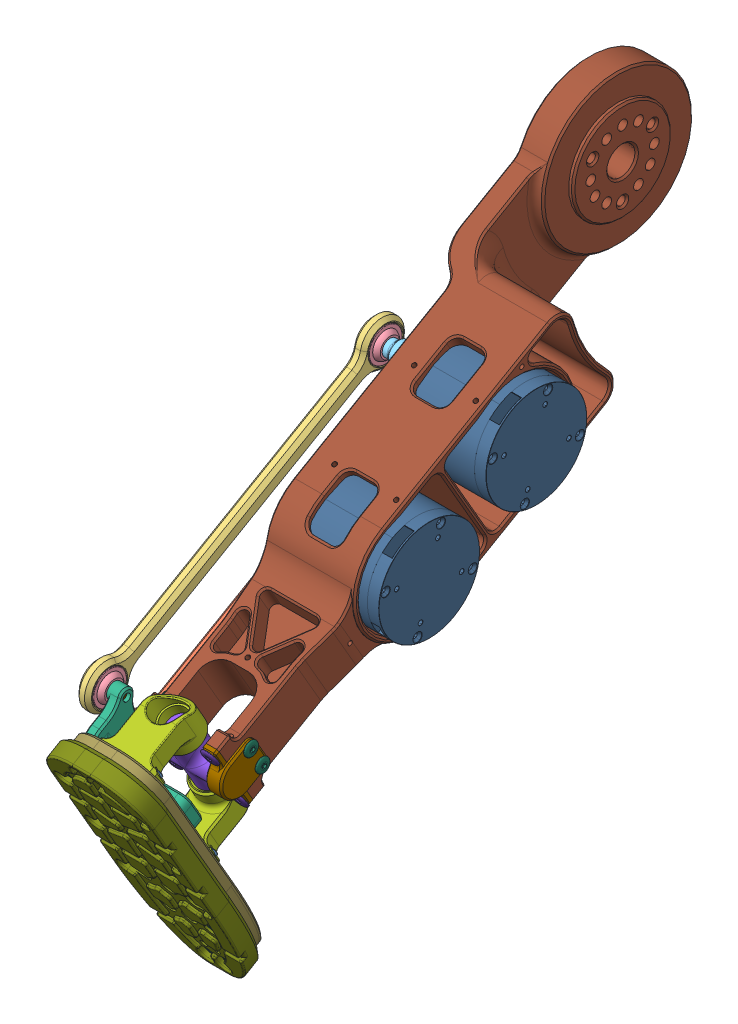
SolidWorks assembly 脚部装配体, configuration 默认. Lengths in mm.
Overall size (85.06 414.51 476.41).
79 component instances, 18 part files, 169 mates.
Components (placement in the parent):
- GB╱T 70.1-2008[内六角圆柱头螺钉M5×10].step-1: GB╱T 70.1-2008[内六角圆柱头螺钉M5×10].step [默认] at (53.6753 -418.9952 565.7229) x (0 0.5 -0.866025) z (0.926695 -0.325466 -0.187908) size (15 8.5 8.5)
- GB╱T 70.1-2008[内六角圆柱头螺钉M5×10].step-2: GB╱T 70.1-2008[内六角圆柱头螺钉M5×10].step [默认] at (67.1753 -418.9952 565.7229) x (0 0.5 -0.866025) z (0.969283 -0.212997 -0.122974) size (15 8.5 8.5)
- GB╱T 70.1-2008[内六角圆柱头螺钉M5×10].step-3: GB╱T 70.1-2008[内六角圆柱头螺钉M5×10].step [默认] at (40.1753 -365.3016 596.7229) x (0 0.5 -0.866025) z (0.993521 -0.098424 -0.056825) size (15 8.5 8.5)
- GB╱T 70.1-2008[内六角圆柱头螺钉M5×10].step-4: GB╱T 70.1-2008[内六角圆柱头螺钉M5×10].step [默认] at (53.6753 -365.3016 596.7229) x (0 0.5 -0.866025) z (1 0.000593 0.000342) size (15 8.5 8.5)
- GB╱T 70.1-2008[内六角圆柱头螺钉M5×10].step-5: GB╱T 70.1-2008[内六角圆柱头螺钉M5×10].step [默认] at (41.1753 -396.4785 578.7229) x (0 0.5 -0.866025) z (0.990502 0.119076 0.068749) size (15 8.5 8.5)
- GB╱T 70.1-2008[内六角圆柱头螺钉M5×10].step-6: GB╱T 70.1-2008[内六角圆柱头螺钉M5×10].step [默认] at (67.1753 -365.3016 596.7229) x (0 0.5 -0.866025) z (0.996407 0.073345 0.042346) size (15 8.5 8.5)
- GB╱T 70.1-2008[内六角圆柱头螺钉M5×10].step-7: GB╱T 70.1-2008[内六角圆柱头螺钉M5×10].step [默认] at (66.1753 -387.8182 583.7229) x (0 0.5 -0.866025) z (0.988477 0.13109 0.075685) size (15 8.5 8.5)
- GB╱T 70.1-2008[内六角圆柱头螺钉M5×10].step-8: GB╱T 70.1-2008[内六角圆柱头螺钉M5×10].step [默认] at (66.1753 -396.4785 578.7229) x (0 0.5 -0.866025) z (0.990906 0.116532 0.06728) size (15 8.5 8.5)
- 短连杆-1: 短连杆 [默认] at (5.8253 -352.7894 433.0512) x (0 0.5 -0.866025) z (-1 0 0) size (135 25 7)
- 长连杆-1: 长连杆 [默认] at (5.8253 -286.4689 358.1807) x (0 0.866025 0.5) z (-1 0 0) size (25 205 7)
- 镜向GB╱T 9163-2001[向心关节轴承（G系列）8]-1: 镜向GB╱T 9163-2001[向心关节轴承（G系列）8] [8] at (11.3253 -335.4689 443.0512) x (1 0 0) z (0 -0.949949 -0.312405) size (11 19 19)
- 镜向GB╱T 9163-2001[向心关节轴承（G系列）8]-2: 镜向GB╱T 9163-2001[向心关节轴承（G系列）8] [8] at (11.3253 -390.4689 538.314) x (1 0 0) z (0 -0.950599 -0.310421) size (11 19 19)
- 镜向GB╱T 9163-2001[向心关节轴承（G系列）8]-3: 镜向GB╱T 9163-2001[向心关节轴承（G系列）8] [8] at (11.3253 -265.8279 402.4294) x (1 0 0) z (0 -0.949949 -0.312405) size (11 19 19)
- 镜向GB╱T 9163-2001[向心关节轴承（G系列）8]-4: 镜向GB╱T 9163-2001[向心关节轴承（G系列）8] [8] at (11.3253 -355.8279 558.314) x (1 0 0) z (0 -0.950599 -0.310421) size (11 19 19)
- 输出法兰连杆-1: 输出法兰连杆 [默认] at (33.0753 -318.1484 453.0512) x (0 -0.5 0.866025) z (-1 0 0) size (35 46.68 33.25)
- 输出法兰连杆-2: 输出法兰连杆 [默认] at (33.0753 -283.1484 392.4294) x (0 0.5 -0.866025) z (-1 0 0) size (35 46.68 33.25)
- 脚底连杆-1: 脚底连杆 [默认] at (53.6753 -369.8279 582.5627) x (0 -0.866025 -0.5) z (0 0.5 -0.866025) size (49 65.35 38.5)
- 脚踝横滚连接件-1: 脚踝横滚连接件 [默认] at (53.6753 -355.8279 558.314) x (0 0.5 -0.866025) z (0 0.866025 0.5) size (40.5 33 22.07)
- 脚踝横滚连接件-2: 脚踝横滚连接件 [默认] at (53.6753 -390.4689 538.314) x (0 0.5 -0.866025) z (0 -0.866025 -0.5) size (40.5 33 22.07)
- 镜向16x40十字轴承-1: 镜向16x40十字轴承 [默认] at (53.6753 -373.1484 548.314) x (1 0 0) z (0 -0.5 0.866025) size (40 40 16)
- 小腿轴承锁-1: 小腿轴承锁 [默认] at (34.3253 -373.1484 548.314) x (0 -0.866025 -0.5) z (0 -0.5 0.866025) size (40 8.92 25.5)
- 小腿轴承锁-2: 小腿轴承锁 [默认] at (73.0253 -373.1484 548.314) x (0 0.866025 0.5) z (0 -0.5 0.866025) size (40 8.92 25.5)
- DM 4340 rau 3505 电机 3D-1: DM 4340 rau 3505 电机 3D [默认] at (33.0753 -318.1484 453.0512) x (0 -0.5 0.866025) z (0 0.866025 0.5) size (57 56.5 57)
- 小腿-1: 小腿 [默认] at (34.3253 -223.1484 288.5064) x (0 0.866025 0.5) z (-1 0 0) size (219.14 409.57 65)
- DM 4340 rau 3505 电机 3D-2: DM 4340 rau 3505 电机 3D [默认] at (33.0753 -283.1484 392.4294) x (0 0.5 -0.866025) z (0 -0.866025 -0.5) size (57 56.5 57)
- 脚底板-1: 脚底板 [默认] at (53.6753 -405.4689 564.2947) x (0 -0.866025 -0.5) z (0 -0.5 0.866025) size (150.3 50.4 10.3)
- GB╱T 70.1-2008[内六角圆柱头螺钉M5×10].step-9: GB╱T 70.1-2008[内六角圆柱头螺钉M5×10].step [默认] at (41.1753 -387.8182 583.7229) x (0 0.5 -0.866025) z (0.995522 0.081868 0.047267) size (15 8.5 8.5)
- GB╱T 70.1-2008[内六角圆柱头螺钉M3×8].step-1: GB╱T 70.1-2008[内六角圆柱头螺钉M3×8].step [默认] at (28.8253 -318.1484 478.0512) x (1 0 0) z (0 0.56861 0.822607) size (11 5.5 5.5)
- GB╱T 70.1-2008[内六角圆柱头螺钉M3×8].step-2: GB╱T 70.1-2008[内六角圆柱头螺钉M3×8].step [默认] at (28.8253 -339.799 440.5512) x (1 0 0) z (0 0.777748 0.628576) size (11 5.5 5.5)
- GB╱T 70.1-2008[内六角圆柱头螺钉M3×8].step-3: GB╱T 70.1-2008[内六角圆柱头螺钉M3×8].step [默认] at (28.8253 -339.799 465.5512) x (1 0 0) z (0 0.694588 0.719408) size (11 5.5 5.5)
- GB╱T 70.1-2008[内六角圆柱头螺钉M3×8].step-4: GB╱T 70.1-2008[内六角圆柱头螺钉M3×8].step [默认] at (28.8253 -283.1484 417.4294) x (1 0 0) z (0 0.062591 0.998039) size (11 5.5 5.5)
- GB╱T 70.1-2008[内六角圆柱头螺钉M3×8].step-5: GB╱T 70.1-2008[内六角圆柱头螺钉M3×8].step [默认] at (28.8253 -296.4977 440.5512) x (1 0 0) z (0 0.264654 0.964343) size (11 5.5 5.5)
- GB╱T 70.1-2008[内六角圆柱头螺钉M3×8].step-6: GB╱T 70.1-2008[内六角圆柱头螺钉M3×8].step [默认] at (28.8253 -261.4977 379.9294) x (1 0 0) z (0 0.404506 0.914535) size (11 5.5 5.5)
- GB╱T 70.1-2008[内六角圆柱头螺钉M3×8].step-7: GB╱T 70.1-2008[内六角圆柱头螺钉M3×8].step [默认] at (28.8253 -318.1484 428.0512) x (1 0 0) z (0 0.1476 0.989047) size (11 5.5 5.5)
- GB╱T 70.1-2008[内六角圆柱头螺钉M3×8].step-8: GB╱T 70.1-2008[内六角圆柱头螺钉M3×8].step [默认] at (28.8253 -304.799 404.9294) x (1 0 0) z (0 0.079506 0.996834) size (11 5.5 5.5)
- GB╱T 70.1-2008[内六角圆柱头螺钉M3×8].step-9: GB╱T 70.1-2008[内六角圆柱头螺钉M3×8].step [默认] at (28.8253 -283.1484 367.4294) x (1 0 0) z (0 0.269776 0.962923) size (11 5.5 5.5)
- GB╱T 70.1-2008[内六角圆柱头螺钉M3×8].step-10: GB╱T 70.1-2008[内六角圆柱头螺钉M3×8].step [默认] at (28.8253 -304.799 379.9294) x (1 0 0) z (0 0.163643 0.98652) size (11 5.5 5.5)
- GB╱T 70.1-2008[内六角圆柱头螺钉M3×8].step-11: GB╱T 70.1-2008[内六角圆柱头螺钉M3×8].step [默认] at (28.8253 -261.4977 404.9294) x (1 0 0) z (0 0.092596 0.995704) size (11 5.5 5.5)
- GB╱T 70.1-2008[内六角圆柱头螺钉M3×8].step-12: GB╱T 70.1-2008[内六角圆柱头螺钉M3×8].step [默认] at (28.8253 -296.4977 465.5512) x (1 0 0) z (0 0.414988 0.909827) size (11 5.5 5.5)
- GB╱T 70.1-2008[内六角圆柱头螺钉M5×10].step-10: GB╱T 70.1-2008[内六角圆柱头螺钉M5×10].step [默认] at (40.1753 -418.9952 565.7229) x (0 0.5 -0.866025) z (0.87612 -0.417505 -0.241047) size (15 8.5 8.5)
- GB╱T 70.1-2008[内六角圆柱头螺钉M3×12].step-1: GB╱T 70.1-2008[内六角圆柱头螺钉M3×12].step [默认] at (24.0753 -318.1484 439.5512) x (1 0 0) z (0 -0.36177 -0.932267) size (15 5.5 5.5)
- GB╱T 70.1-2008[内六角圆柱头螺钉M3×12].step-2: GB╱T 70.1-2008[内六角圆柱头螺钉M3×12].step [默认] at (24.0753 -306.457 446.3012) x (1 0 0) z (0 -0.188949 -0.981987) size (15 5.5 5.5)
- GB╱T 70.1-2008[内六角圆柱头螺钉M3×12].step-3: GB╱T 70.1-2008[内六角圆柱头螺钉M3×12].step [默认] at (24.0753 -306.457 459.8012) x (1 0 0) z (0 -0.027361 -0.999626) size (15 5.5 5.5)
- GB╱T 70.1-2008[内六角圆柱头螺钉M3×12].step-4: GB╱T 70.1-2008[内六角圆柱头螺钉M3×12].step [默认] at (24.0753 -329.8397 459.8012) x (1 0 0) z (0 0.162549 -0.9867) size (15 5.5 5.5)
- GB╱T 70.1-2008[内六角圆柱头螺钉M3×12].step-5: GB╱T 70.1-2008[内六角圆柱头螺钉M3×12].step [默认] at (24.0753 -294.8397 385.6794) x (1 0 0) z (0 0.075463 -0.997149) size (15 5.5 5.5)
- GB╱T 70.1-2008[内六角圆柱头螺钉M3×12].step-6: GB╱T 70.1-2008[内六角圆柱头螺钉M3×12].step [默认] at (24.0753 -294.8397 399.1794) x (1 0 0) z (0 0.148351 -0.988935) size (15 5.5 5.5)
- GB╱T 70.1-2008[内六角圆柱头螺钉M3×12].step-7: GB╱T 70.1-2008[内六角圆柱头螺钉M3×12].step [默认] at (24.0753 -283.1484 378.9294) x (1 0 0) z (0 -0.035607 -0.999366) size (15 5.5 5.5)
- GB╱T 70.1-2008[内六角圆柱头螺钉M3×12].step-8: GB╱T 70.1-2008[内六角圆柱头螺钉M3×12].step [默认] at (24.0753 -271.457 385.6794) x (1 0 0) z (0 -0.180885 -0.983504) size (15 5.5 5.5)
- GB╱T 70.1-2008[内六角圆柱头螺钉M3×12].step-9: GB╱T 70.1-2008[内六角圆柱头螺钉M3×12].step [默认] at (24.0753 -318.1484 466.5512) x (1 0 0) z (0 0.093899 -0.995582) size (15 5.5 5.5)
- GB╱T 70.1-2008[内六角圆柱头螺钉M3×12].step-10: GB╱T 70.1-2008[内六角圆柱头螺钉M3×12].step [默认] at (24.0753 -283.1484 405.9294) x (1 0 0) z (0 0.179037 -0.983842) size (15 5.5 5.5)
- 平头M4x10螺丝-1: 平头M4x10螺丝 [默认] at (41.7098 -450.973 552.1102) x (-0.969156 0.21343 0.123224) z (-0.246448 -0.839314 -0.484578) size (8.17 11.21 8.17)
- 平头M4x10螺丝-2: 平头M4x10螺丝 [默认] at (58.6753 -478.2528 536.3602) x (-0.997864 0.05657 0.032661) z (-0.065321 -0.864176 -0.498932) size (8.17 11.21 8.17)
- 平头M4x10螺丝-3: 平头M4x10螺丝 [默认] at (75.6753 -428.8894 564.8602) x (-0.954336 -0.258712 -0.149368) z (0.298735 -0.826479 -0.477168) size (8.17 11.21 8.17)
- 平头M4x10螺丝-4: 平头M4x10螺丝 [默认] at (67.6637 -430.6214 563.8602) x (-0.904419 -0.369487 -0.213323) z (0.426646 -0.783249 -0.452209) size (8.17 11.21 8.17)
- 平头M4x10螺丝-5: 平头M4x10螺丝 [默认] at (48.6753 -478.2528 536.3602) x (-0.991805 -0.110645 -0.063881) z (0.127762 -0.858928 -0.495902) size (8.17 11.21 8.17)
- 平头M4x10螺丝-6: 平头M4x10螺丝 [默认] at (53.675 -430.6214 563.8602) x (-0.861891 -0.439155 -0.253546) z (0.507093 -0.74642 -0.430946) size (8.17 11.21 8.17)
- 平头M4x10螺丝-7: 平头M4x10螺丝 [默认] at (65.6407 -450.973 552.1102) x (-0.969156 0.21343 0.123224) z (-0.246448 -0.839314 -0.484578) size (8.17 11.21 8.17)
- 平头M4x10螺丝-8: 平头M4x10螺丝 [默认] at (53.6752 -450.973 552.1102) x (-0.969156 0.21343 0.123224) z (-0.246448 -0.839314 -0.484578) size (8.17 11.21 8.17)
- 平头M4x10螺丝-9: 平头M4x10螺丝 [默认] at (39.6862 -430.6214 563.8602) x (-0.838812 -0.471482 -0.27221) z (0.544421 -0.726433 -0.419406) size (8.17 11.21 8.17)
- 平头M4x10螺丝-10: 平头M4x10螺丝 [默认] at (31.6753 -398.5785 582.3602) x (-0.861891 -0.439155 -0.253546) z (0.507093 -0.74642 -0.430946) size (8.17 11.21 8.17)
- 平头M4x10螺丝-11: 平头M4x10螺丝 [默认] at (75.6753 -398.5785 582.3602) x (-0.92323 -0.332769 -0.192124) z (0.384249 -0.79954 -0.461615) size (8.17 11.21 8.17)
- 平头M4x10螺丝-12: 平头M4x10螺丝 [默认] at (31.6753 -368.2676 599.8602) x (-0.812228 -0.505188 -0.29167) z (0.583341 -0.70341 -0.406114) size (8.17 11.21 8.17)
- 橡胶脚底-1: 橡胶脚底 [默认] at (53.6753 -409.4689 571.2229) x (0 -0.866025 -0.5) z (0 -0.5 0.866025) size (159.99 63.94 16.1)
- 平头M4x10螺丝-13: 平头M4x10螺丝 [默认] at (58.6753 -353.5452 608.3602) x (-0.78634 -0.535025 -0.308897) z (0.617794 -0.68099 -0.39317) size (8.17 11.21 8.17)
- 平头M4x10螺丝-14: 平头M4x10螺丝 [默认] at (75.6753 -368.2676 599.8602) x (-0.812228 -0.505188 -0.29167) z (0.583341 -0.70341 -0.406114) size (8.17 11.21 8.17)
- 平头M4x10螺丝-15: 平头M4x10螺丝 [默认] at (48.6753 -353.5452 608.3602) x (-0.785851 -0.535564 -0.309208) z (0.618416 -0.680567 -0.392926) size (8.17 11.21 8.17)
- 平头M4x10螺丝-16: 平头M4x10螺丝 [默认] at (31.6753 -428.8894 564.8602) x (-0.839243 -0.470907 -0.271878) z (0.543757 -0.726806 -0.419621) size (8.17 11.21 8.17)
- 平头M5x10螺丝-1: 平头M5x10螺丝 [默认] at (72.1378 -360.9765 560.3066) x (0.907869 -0.363085 -0.209627) z (0.419255 0.786237 0.453934) size (9.7 11.31 9.7)
- 平头M5x10螺丝-2: 平头M5x10螺丝 [默认] at (35.2128 -389.6203 543.7691) x (0.951881 -0.265409 -0.153234) z (0.306468 0.824353 0.475941) size (9.7 11.31 9.7)
- 平头M5x10螺丝-3: 平头M5x10螺丝 [默认] at (35.2128 -360.9765 560.3066) x (0.954332 -0.258724 -0.149375) z (0.298749 0.826475 0.477166) size (9.7 11.31 9.7)
- 平头M5x16螺丝-1: 平头M5x16螺丝 [默认] at (4.5253 -390.4689 538.314) x (0 -0.807772 0.589495) z (0 0.589495 0.807772) size (9.7 17.31 9.7)
- 平头M4x10螺丝-17: 平头M4x10螺丝 [默认] at (78.8003 -373.2775 535.5377) x (0 0.225404 0.974265) z (0 -0.974265 0.225404) size (8.17 11.21 8.17)
- 平头M5x16螺丝-2: 平头M5x16螺丝 [默认] at (4.5253 -265.8279 402.4294) x (0 -0.562407 0.82686) z (0 0.82686 0.562407) size (9.7 17.31 9.7)
- 平头M4x10螺丝-18: 平头M4x10螺丝 [默认] at (78.8003 -362.0192 542.0377) x (0 0.129 0.991645) z (0 -0.991645 0.129) size (8.17 11.21 8.17)
- 平头M5x10螺丝-4: 平头M5x10螺丝 [默认] at (72.1378 -389.6203 543.7691) x (0.937952 -0.300306 -0.173382) z (0.346764 0.812291 0.468976) size (9.7 11.31 9.7)
- 平头M5x16螺丝-3: 平头M5x16螺丝 [默认] at (4.5253 -355.8279 558.314) x (0 -0.870122 0.492837) z (0 0.492837 0.870122) size (9.7 17.31 9.7)
- 平头M5x16螺丝-4: 平头M5x16螺丝 [默认] at (4.5253 -335.4689 443.0512) x (0 -0.707938 0.706274) z (0 0.706274 0.707938) size (9.7 17.31 9.7)
- 平头M4x10螺丝-19: 平头M4x10螺丝 [默认] at (28.5503 -373.2775 535.5377) x (0 0.397095 -0.917778) z (0 -0.917778 -0.397095) size (8.17 11.21 8.17)
- 平头M4x10螺丝-20: 平头M4x10螺丝 [默认] at (28.5503 -362.0192 542.0377) x (0 0.276376 -0.961049) z (0 -0.961049 -0.276376) size (8.17 11.21 8.17)
Mates (geometry in assembly coordinates):
- 同心1: concentric aligned: cylinder of 短连杆-1 through (151.6206 -390.4689 538.314) axis (-1 0 0) radius 9.5; cylinder of 镜向GB╱T 9163-2001[向心关节轴承（G系列）8]-2 through (4.3253 -390.4689 538.314) axis (-1 0 0) radius 9.5
- 重合1: coincident anti-aligned: plane of 短连杆-1 through (8.3253 -390.4689 538.314) normal (1 0 0); plane of 镜向GB╱T 9163-2001[向心关节轴承（G系列）8]-2 through (8.3253 -392.752 545.3057) normal (-1 0 0)
- 同心2: concentric aligned: cylinder of 长连杆-1 through (220.8441 -265.8279 402.4294) axis (-1 0 0) radius 9.5; cylinder of 镜向GB╱T 9163-2001[向心关节轴承（G系列）8]-3 through (4.3253 -265.8279 402.4294) axis (-1 0 0) radius 9.5
- 重合2: coincident anti-aligned: plane of 短连杆-1 through (8.3253 -390.4689 538.314) normal (1 0 0); plane of 镜向GB╱T 9163-2001[向心关节轴承（G系列）8]-1 through (8.3253 -337.7666 450.0381) normal (-1 0 0)
- 同心3: concentric aligned: cylinder of 短连杆-1 through (151.6206 -335.4689 443.0512) axis (-1 0 0) radius 9.5; cylinder of 镜向GB╱T 9163-2001[向心关节轴承（G系列）8]-1 through (4.3253 -335.4689 443.0512) axis (-1 0 0) radius 9.5
- 同心4: concentric aligned: cylinder of 长连杆-1 through (220.8441 -355.8279 558.314) axis (-1 0 0) radius 9.5; cylinder of 镜向GB╱T 9163-2001[向心关节轴承（G系列）8]-4 through (4.3253 -355.8279 558.314) axis (-1 0 0) radius 9.5
- 重合3: coincident anti-aligned: plane of 小腿轴承锁-1 through (34.3253 -373.1484 548.314) normal (0 0.5 -0.866025); plane of 小腿-1 through (6.5253 -361.024 555.314) normal (0 -0.5 0.866025)
- 重合4: coincident anti-aligned: plane of 小腿轴承锁-2 through (75.6003 -373.1484 548.314) normal (-1 0 0); plane of 小腿-1 through (75.6003 -414.7176 524.314) normal (1 0 0)
- 重合5: coincident anti-aligned: plane of 小腿轴承锁-1 through (31.7503 -373.1484 548.314) normal (1 0 0); plane of 小腿-1 through (31.7503 -414.7176 524.314) normal (-1 0 0)
- 同心5: concentric aligned: cylinder of 小腿轴承锁-1 through (35.2128 -355.0765 550.0875) axis (0 -0.5 0.866025) radius 2.575; cylinder of 小腿-1 through (35.2128 -358.8265 556.5827) axis (0 -0.5 0.866025) radius 2.1
- 同心6: concentric aligned: cylinder of 小腿轴承锁-2 through (98.2278 -373.1484 548.314) axis (-1 0 0) radius 8; cylinder of 小腿-1 through (79.8253 -373.1484 548.314) axis (-1 0 0) radius 8
- 重合6: coincident anti-aligned: plane of 小腿-1 through (34.8253 -223.1484 288.5064) normal (1 0 0); plane of DM 4340 rau 3505 电机 3D-2 through (34.8253 -273.6484 375.9749) normal (-1 0 0)
- 同心7: concentric aligned: cylinder of 小腿-1 through (28.8253 -304.799 379.9294) axis (-1 0 0) radius 3.25; cylinder of DM 4340 rau 3505 电机 3D-2 through (34.8253 -304.799 379.9294) axis (-1 0 0) radius 1.25
- 同心8: concentric anti-aligned: cylinder of 镜向16x40十字轴承-1 through (73.6753 -373.1484 548.314) axis (-1 0 0) radius 8; cylinder of 小腿轴承锁-2 through (65.1003 -373.1484 548.314) axis (1 0 0) radius 8
- 重合7: coincident anti-aligned: plane of 镜向16x40十字轴承-1 through (73.6753 -373.1484 548.314) normal (1 0 0); plane of 小腿轴承锁-2 through (73.6753 -373.1484 548.314) normal (-1 0 0)
- 重合8: coincident anti-aligned: plane of 小腿轴承锁-2 through (73.0253 -373.1484 548.314) normal (0 0.5 -0.866025); plane of 小腿-1 through (6.5253 -361.024 555.314) normal (0 -0.5 0.866025)
- 同心9: concentric aligned: cylinder of 小腿-1 through (28.8253 -261.4977 404.9294) axis (-1 0 0) radius 3.25; cylinder of DM 4340 rau 3505 电机 3D-2 through (34.8253 -261.4977 404.9294) axis (-1 0 0) radius 1.25
- 同心10: concentric anti-aligned: cylinder of 脚踝横滚连接件-1 through (53.6753 -360.158 555.814) axis (0 0.866025 0.5) radius 8; cylinder of 镜向16x40十字轴承-1 through (53.6753 -355.8279 558.314) axis (0 -0.866025 -0.5) radius 8
- 重合9: coincident anti-aligned: plane of DM 4340 rau 3505 电机 3D-1 through (34.8253 -327.6484 469.5057) normal (-1 0 0); plane of 小腿-1 through (34.8253 -223.1484 288.5064) normal (1 0 0)
- 同心11: concentric aligned: cylinder of DM 4340 rau 3505 电机 3D-1 through (34.8253 -296.4977 465.5512) axis (-1 0 0) radius 1.25; cylinder of 小腿-1 through (28.8253 -296.4977 465.5512) axis (-1 0 0) radius 3.25
- 同心12: concentric aligned: cylinder of DM 4340 rau 3505 电机 3D-1 through (34.8253 -339.799 440.5512) axis (-1 0 0) radius 1.25; cylinder of 小腿-1 through (28.8253 -339.799 440.5512) axis (-1 0 0) radius 1.6
- 重合10: coincident anti-aligned: plane of 脚底连杆-1 through (53.6753 -369.8279 582.5627) normal (0 -0.5 0.866025); plane of 脚底板-1 through (58.6753 -361.1676 587.5627) normal (0 0.5 -0.866025)
- 重合11: coincident anti-aligned: plane of 脚踝横滚连接件-1 through (53.6753 -355.8279 558.314) normal (0 -0.866025 -0.5); plane of 镜向16x40十字轴承-1 through (53.6753 -355.8279 558.314) normal (0 0.866025 0.5)
- 重合12: coincident anti-aligned: plane of 脚踝横滚连接件-2 through (53.6753 -390.4689 538.314) normal (0 0.866025 0.5); plane of 镜向16x40十字轴承-1 through (53.6753 -390.4689 538.314) normal (0 -0.866025 -0.5)
- 同心13: concentric aligned: cylinder of 脚踝横滚连接件-2 through (53.6753 -390.4689 538.314) axis (0 -0.866025 -0.5) radius 7; cylinder of 镜向16x40十字轴承-1 through (53.6753 -355.8279 558.314) axis (0 -0.866025 -0.5) radius 8
- 重合13: coincident anti-aligned: plane of 脚底连杆-1 through (61.1753 -387.9833 579.0088) normal (0 0.866025 0.5); plane of 脚底板-1 through (61.1753 -384.4833 572.9467) normal (0 -0.866025 -0.5)
- 重合14: coincident anti-aligned: plane of 脚踝横滚连接件-1 through (53.6753 -351.4977 560.814) normal (0 -0.866025 -0.5); plane of 脚底板-1 through (70.1753 -365.4977 585.0627) normal (0 0.866025 0.5)
- 重合15: coincident anti-aligned: plane of 脚踝横滚连接件-1 through (37.1753 -355.8279 558.314) normal (-1 0 0); plane of 脚底板-1 through (37.1753 -355.1054 591.0627) normal (1 0 0)
- 同心14: concentric anti-aligned: cylinder of 镜向GB╱T 9163-2001[向心关节轴承（G系列）8]-3 through (4.3253 -265.8279 402.4294) axis (-1 0 0) radius 4; cylinder of 输出法兰连杆-2 through (5.8253 -265.8279 402.4294) axis (1 0 0) radius 4
- 重合16: coincident anti-aligned: plane of 输出法兰连杆-2 through (33.0753 -283.1484 392.4294) normal (1 0 0); plane of DM 4340 rau 3505 电机 3D-2 through (33.0753 -280.7734 388.3158) normal (-1 0 0)
- 重合17: coincident anti-aligned: plane of 脚踝横滚连接件-2 through (43.1753 -420.1913 555.7947) normal (0 -0.5 0.866025); plane of 脚底板-1 through (53.6753 -405.4689 564.2947) normal (0 0.5 -0.866025)
- 同心15: concentric anti-aligned: cylinder of 输出法兰连杆-1 through (25.0753 -318.1484 453.0512) axis (1 0 0) radius 9.5; cylinder of 小腿-1 through (97.8253 -318.1484 453.0512) axis (-1 0 0) radius 21
- 重合18: coincident anti-aligned: plane of 脚踝横滚连接件-1 through (64.1753 -356.1054 592.7947) normal (0 -0.5 0.866025); plane of 脚底板-1 through (53.6753 -405.4689 564.2947) normal (0 0.5 -0.866025)
- 重合19: coincident anti-aligned: plane of 镜向GB╱T 9163-2001[向心关节轴承（G系列）8]-3 through (16.8253 -267.5461 407.6541) normal (1 0 0); plane of 输出法兰连杆-2 through (16.8253 -318.0779 492.9291) normal (-1 0 0)
- 重合20: coincident anti-aligned: plane of 脚底连杆-1 through (61.1753 -392.3134 576.5088) normal (1 0 0); plane of 脚底板-1 through (61.1753 -384.4833 572.9467) normal (-1 0 0)
- 同心16: concentric anti-aligned: cylinder of 输出法兰连杆-2 through (25.0753 -283.1484 392.4294) axis (1 0 0) radius 9.5; cylinder of DM 4340 rau 3505 电机 3D-2 through (33.0753 -283.1484 392.4294) axis (-1 0 0) radius 4.75
- 重合21: coincident anti-aligned: plane of 输出法兰连杆-1 through (33.0753 -318.1484 453.0512) normal (1 0 0); plane of DM 4340 rau 3505 电机 3D-1 through (33.0753 -320.5234 457.1648) normal (-1 0 0)
- 同心17: concentric anti-aligned: cylinder of 镜向GB╱T 9163-2001[向心关节轴承（G系列）8]-1 through (4.3253 -335.4689 443.0512) axis (-1 0 0) radius 4; cylinder of 输出法兰连杆-1 through (5.8253 -335.4689 443.0512) axis (1 0 0) radius 4
- 同心18: concentric anti-aligned: cylinder of 镜向GB╱T 9163-2001[向心关节轴承（G系列）8]-2 through (4.3253 -390.4689 538.314) axis (-1 0 0) radius 4; cylinder of 脚底连杆-1 through (5.8253 -390.4689 538.314) axis (1 0 0) radius 4
- 重合22: coincident anti-aligned: plane of 镜向GB╱T 9163-2001[向心关节轴承（G系列）8]-1 through (16.8253 -337.1871 448.2759) normal (1 0 0); plane of 输出法兰连杆-1 through (16.8253 -283.2189 352.5515) normal (-1 0 0)
- 重合23: coincident anti-aligned: plane of 镜向GB╱T 9163-2001[向心关节轴承（G系列）8]-2 through (16.8253 -392.1762 543.5423) normal (1 0 0); plane of 脚底连杆-1 through (16.8253 -390.4689 538.314) normal (-1 0 0)
- 同心19: concentric anti-aligned: cylinder of 镜向GB╱T 9163-2001[向心关节轴承（G系列）8]-4 through (4.3253 -355.8279 558.314) axis (-1 0 0) radius 4; cylinder of 脚底连杆-1 through (5.8253 -355.8279 558.314) axis (1 0 0) radius 4
- 重合24: coincident anti-aligned: plane of 镜向GB╱T 9163-2001[向心关节轴承（G系列）8]-4 through (16.8253 -357.5352 563.5423) normal (1 0 0); plane of 脚底连杆-1 through (16.8253 -355.8279 558.314) normal (-1 0 0)
- 重合25: coincident anti-aligned: plane of 长连杆-1 through (8.3253 -334.6682 550.6643) normal (1 0 0); plane of 镜向GB╱T 9163-2001[向心关节轴承（G系列）8]-3 through (8.3253 -268.1256 409.4163) normal (-1 0 0)
- 重合26: coincident anti-aligned: plane of 长连杆-1 through (8.3253 -334.6682 550.6643) normal (1 0 0); plane of 镜向GB╱T 9163-2001[向心关节轴承（G系列）8]-4 through (8.3253 -358.111 565.3057) normal (-1 0 0)
- 同心20: concentric anti-aligned: cylinder of GB╱T 70.1-2008[内六角圆柱头螺钉M5×10].step-6 through (67.1753 -365.3016 596.7229) axis (0 0.5 -0.866025) radius 2.5; cylinder of 脚底板-1 through (67.1753 -358.8016 585.4646) axis (0 -0.5 0.866025) radius 2.65
- 同心21: concentric anti-aligned: cylinder of GB╱T 70.1-2008[内六角圆柱头螺钉M5×10].step-7 through (66.1753 -387.8182 583.7229) axis (0 0.5 -0.866025) radius 2.5; cylinder of 脚底板-1 through (66.1753 -382.3182 574.1967) axis (0 -0.5 0.866025) radius 2.65
- 重合27: coincident anti-aligned: plane of GB╱T 70.1-2008[内六角圆柱头螺钉M5×10].step-7 through (65.532 -381.68 581.4933) normal (0 0.5 -0.866025); plane of 脚底板-1 through (70.1697 -448.9934 542.6299) normal (0 -0.5 0.866025)
- 重合28: coincident anti-aligned: plane of GB╱T 70.1-2008[内六角圆柱头螺钉M5×10].step-8 through (65.6035 -390.3314 576.4985) normal (0 0.5 -0.866025); plane of 脚底板-1 through (70.1697 -448.9934 542.6299) normal (0 -0.5 0.866025)
- 重合29: coincident anti-aligned: plane of 脚底板-1 through (70.1697 -448.9934 542.6299) normal (0 -0.5 0.866025); plane of GB╱T 70.1-2008[内六角圆柱头螺钉M5×10].step-9 through (40.7736 -381.6541 581.5083) normal (0 0.5 -0.866025)
- 同心22: concentric anti-aligned: cylinder of 脚底板-1 through (41.1753 -382.3182 574.1967) axis (0 -0.5 0.866025) radius 2.65; cylinder of GB╱T 70.1-2008[内六角圆柱头螺钉M5×10].step-9 through (41.1753 -387.8182 583.7229) axis (0 0.5 -0.866025) radius 2.5
- 同心23: concentric anti-aligned: cylinder of GB╱T 70.1-2008[内六角圆柱头螺钉M5×10].step-5 through (41.1753 -396.4785 578.7229) axis (0 0.5 -0.866025) radius 2.5; cylinder of 脚底板-1 through (41.1753 -390.9785 569.1967) axis (0 -0.5 0.866025) radius 2.65
- 重合30: coincident anti-aligned: plane of GB╱T 70.1-2008[内六角圆柱头螺钉M5×10].step-5 through (40.591 -390.3328 576.4976) normal (0 0.5 -0.866025); plane of 脚底板-1 through (70.1697 -448.9934 542.6299) normal (0 -0.5 0.866025)
- 同心24: concentric anti-aligned: cylinder of GB╱T 70.1-2008[内六角圆柱头螺钉M5×10].step-8 through (66.1753 -396.4785 578.7229) axis (0 0.5 -0.866025) radius 2.5; cylinder of 脚底板-1 through (66.1753 -390.9785 569.1967) axis (0 -0.5 0.866025) radius 2.65
- 重合31: coincident anti-aligned: plane of GB╱T 70.1-2008[内六角圆柱头螺钉M5×10].step-6 through (66.8154 -359.1342 594.5102) normal (0 0.5 -0.866025); plane of 脚底板-1 through (70.1697 -448.9934 542.6299) normal (0 -0.5 0.866025)
- 重合32: coincident anti-aligned: plane of 脚底板-1 through (70.1697 -448.9934 542.6299) normal (0 -0.5 0.866025); plane of GB╱T 70.1-2008[内六角圆柱头螺钉M5×10].step-10 through (42.2242 -413.2705 563.2546) normal (0 0.5 -0.866025)
- 同心25: concentric anti-aligned: cylinder of GB╱T 70.1-2008[内六角圆柱头螺钉M5×10].step-1 through (53.6753 -418.9952 565.7229) axis (0 0.5 -0.866025) radius 2.5; cylinder of 脚底板-1 through (53.6753 -412.4952 554.4646) axis (0 -0.5 0.866025) radius 2.65
- 重合33: coincident anti-aligned: plane of GB╱T 70.1-2008[内六角圆柱头螺钉M5×10].step-4 through (53.6724 -359.121 594.5178) normal (0 0.5 -0.866025); plane of 脚底板-1 through (70.1697 -448.9934 542.6299) normal (0 -0.5 0.866025)
- 同心26: concentric anti-aligned: cylinder of GB╱T 70.1-2008[内六角圆柱头螺钉M5×10].step-4 through (53.6753 -365.3016 596.7229) axis (0 0.5 -0.866025) radius 2.5; cylinder of 脚底板-1 through (53.6753 -358.8016 585.4646) axis (0 -0.5 0.866025) radius 2.65
- 重合34: coincident anti-aligned: plane of GB╱T 70.1-2008[内六角圆柱头螺钉M5×10].step-3 through (40.6584 -359.1448 594.504) normal (0 0.5 -0.866025); plane of 脚底板-1 through (70.1697 -448.9934 542.6299) normal (0 -0.5 0.866025)
- 重合35: coincident anti-aligned: plane of GB╱T 70.1-2008[内六角圆柱头螺钉M5×10].step-2 through (68.2206 -412.9276 563.4525) normal (0 0.5 -0.866025); plane of 脚底板-1 through (70.1697 -448.9934 542.6299) normal (0 -0.5 0.866025)
- 同心27: concentric anti-aligned: cylinder of GB╱T 70.1-2008[内六角圆柱头螺钉M5×10].step-3 through (40.1753 -365.3016 596.7229) axis (0 0.5 -0.866025) radius 2.5; cylinder of 脚底板-1 through (40.1753 -358.8016 585.4646) axis (0 -0.5 0.866025) radius 2.65
- 同心28: concentric anti-aligned: cylinder of GB╱T 70.1-2008[内六角圆柱头螺钉M5×10].step-2 through (67.1753 -418.9952 565.7229) axis (0 0.5 -0.866025) radius 2.5; cylinder of 脚底板-1 through (67.1753 -412.4952 554.4646) axis (0 -0.5 0.866025) radius 2.65
- 重合36: coincident anti-aligned: plane of GB╱T 70.1-2008[内六角圆柱头螺钉M5×10].step-1 through (55.2726 -413.0844 563.362) normal (0 0.5 -0.866025); plane of 脚底板-1 through (70.1697 -448.9934 542.6299) normal (0 -0.5 0.866025)
- 同心29: concentric anti-aligned: cylinder of 脚底板-1 through (40.1753 -412.4952 554.4646) axis (0 -0.5 0.866025) radius 2.65; cylinder of GB╱T 70.1-2008[内六角圆柱头螺钉M5×10].step-10 through (40.1753 -418.9952 565.7229) axis (0 0.5 -0.866025) radius 2.5
- 同心30: concentric anti-aligned: cylinder of 小腿-1 through (28.8253 -261.4977 379.9294) axis (-1 0 0) radius 1.6; cylinder of GB╱T 70.1-2008[内六角圆柱头螺钉M3×8].step-6 through (28.8253 -261.4977 379.9294) axis (1 0 0) radius 1.5
- 同心31: concentric anti-aligned: cylinder of 小腿-1 through (28.8253 -304.799 379.9294) axis (-1 0 0) radius 1.6; cylinder of GB╱T 70.1-2008[内六角圆柱头螺钉M3×8].step-10 through (28.8253 -304.799 379.9294) axis (1 0 0) radius 1.5
- 重合37: coincident anti-aligned: plane of 小腿-1 through (31.8253 -260.1121 380.7294) normal (-1 0 0); plane of GB╱T 70.1-2008[内六角圆柱头螺钉M3×8].step-11 through (31.8253 -258.7595 404.6748) normal (1 0 0)
- 重合38: coincident anti-aligned: plane of 小腿-1 through (31.8253 -260.1121 380.7294) normal (-1 0 0); plane of GB╱T 70.1-2008[内六角圆柱头螺钉M3×8].step-6 through (31.8253 -258.9828 378.817) normal (1 0 0)
- 同心32: concentric anti-aligned: cylinder of 小腿-1 through (28.8253 -261.4977 404.9294) axis (-1 0 0) radius 1.6; cylinder of GB╱T 70.1-2008[内六角圆柱头螺钉M3×8].step-11 through (28.8253 -261.4977 404.9294) axis (1 0 0) radius 1.5
- 同心33: concentric anti-aligned: cylinder of 小腿-1 through (28.8253 -283.1484 417.4294) axis (-1 0 0) radius 1.6; cylinder of GB╱T 70.1-2008[内六角圆柱头螺钉M3×8].step-4 through (28.8253 -283.1484 417.4294) axis (1 0 0) radius 1.5
- 重合39: coincident anti-aligned: plane of 小腿-1 through (31.8253 -260.1121 380.7294) normal (-1 0 0); plane of GB╱T 70.1-2008[内六角圆柱头螺钉M3×8].step-10 through (31.8253 -302.0861 379.4794) normal (1 0 0)
- 重合40: coincident anti-aligned: plane of 小腿-1 through (31.8253 -260.1121 380.7294) normal (-1 0 0); plane of GB╱T 70.1-2008[内六角圆柱头螺钉M3×8].step-4 through (31.8253 -280.4038 417.2573) normal (1 0 0)
- 重合41: coincident anti-aligned: plane of 小腿-1 through (31.8253 -260.1121 380.7294) normal (-1 0 0); plane of GB╱T 70.1-2008[内六角圆柱头螺钉M3×8].step-8 through (31.8253 -302.0577 404.7108) normal (1 0 0)
- 同心34: concentric anti-aligned: cylinder of 小腿-1 through (28.8253 -304.799 404.9294) axis (-1 0 0) radius 1.6; cylinder of GB╱T 70.1-2008[内六角圆柱头螺钉M3×8].step-8 through (28.8253 -304.799 404.9294) axis (1 0 0) radius 1.5
- 重合42: coincident anti-aligned: plane of 小腿-1 through (31.8253 -260.1121 380.7294) normal (-1 0 0); plane of GB╱T 70.1-2008[内六角圆柱头螺钉M3×8].step-7 through (31.8253 -315.4285 427.6453) normal (1 0 0)
- 重合43: coincident anti-aligned: plane of 小腿-1 through (31.8253 -260.1121 380.7294) normal (-1 0 0); plane of GB╱T 70.1-2008[内六角圆柱头螺钉M3×8].step-9 through (31.8253 -280.5003 366.6875) normal (1 0 0)
- 同心35: concentric anti-aligned: cylinder of 小腿-1 through (28.8253 -283.1484 367.4294) axis (-1 0 0) radius 1.6; cylinder of GB╱T 70.1-2008[内六角圆柱头螺钉M3×8].step-9 through (28.8253 -283.1484 367.4294) axis (1 0 0) radius 1.5
- 重合44: coincident anti-aligned: plane of 小腿-1 through (31.8253 -260.1121 380.7294) normal (-1 0 0); plane of GB╱T 70.1-2008[内六角圆柱头螺钉M3×8].step-5 through (31.8253 -293.8458 439.8234) normal (1 0 0)
- 同心36: concentric anti-aligned: cylinder of 小腿-1 through (28.8253 -318.1484 428.0512) axis (-1 0 0) radius 1.6; cylinder of GB╱T 70.1-2008[内六角圆柱头螺钉M3×8].step-7 through (28.8253 -318.1484 428.0512) axis (1 0 0) radius 1.5
- 同心37: concentric anti-aligned: cylinder of 小腿-1 through (28.8253 -339.799 440.5512) axis (-1 0 0) radius 1.6; cylinder of GB╱T 70.1-2008[内六角圆柱头螺钉M3×8].step-2 through (28.8253 -339.799 440.5512) axis (1 0 0) radius 1.5
- 同心38: concentric anti-aligned: cylinder of 小腿-1 through (28.8253 -296.4977 465.5512) axis (-1 0 0) radius 1.6; cylinder of GB╱T 70.1-2008[内六角圆柱头螺钉M3×8].step-12 through (28.8253 -296.4977 465.5512) axis (1 0 0) radius 1.5
- 同心39: concentric anti-aligned: cylinder of 小腿-1 through (28.8253 -318.1484 478.0512) axis (-1 0 0) radius 1.6; cylinder of GB╱T 70.1-2008[内六角圆柱头螺钉M3×8].step-1 through (28.8253 -318.1484 478.0512) axis (1 0 0) radius 1.5
- 重合45: coincident anti-aligned: plane of 小腿-1 through (31.8253 -260.1121 380.7294) normal (-1 0 0); plane of GB╱T 70.1-2008[内六角圆柱头螺钉M3×8].step-3 through (31.8253 -337.8206 463.6411) normal (1 0 0)
- 重合46: coincident anti-aligned: plane of 小腿-1 through (31.8253 -260.1121 380.7294) normal (-1 0 0); plane of GB╱T 70.1-2008[内六角圆柱头螺钉M3×8].step-2 through (31.8253 -338.0704 438.4124) normal (1 0 0)
- 重合47: coincident anti-aligned: plane of 小腿-1 through (31.8253 -260.1121 380.7294) normal (-1 0 0); plane of GB╱T 70.1-2008[内六角圆柱头螺钉M3×8].step-12 through (31.8253 -293.9957 464.41) normal (1 0 0)
- 同心40: concentric anti-aligned: cylinder of 小腿-1 through (28.8253 -339.799 465.5512) axis (-1 0 0) radius 1.6; cylinder of GB╱T 70.1-2008[内六角圆柱头螺钉M3×8].step-3 through (28.8253 -339.799 465.5512) axis (1 0 0) radius 1.5
- 重合48: coincident anti-aligned: plane of 小腿-1 through (31.8253 -260.1121 380.7294) normal (-1 0 0); plane of GB╱T 70.1-2008[内六角圆柱头螺钉M3×8].step-1 through (31.8253 -315.8862 476.4875) normal (1 0 0)
- 同心41: concentric anti-aligned: cylinder of 小腿-1 through (28.8253 -296.4977 440.5512) axis (-1 0 0) radius 1.6; cylinder of GB╱T 70.1-2008[内六角圆柱头螺钉M3×8].step-5 through (28.8253 -296.4977 440.5512) axis (1 0 0) radius 1.5
- 同心42: concentric anti-aligned: cylinder of 输出法兰连杆-2 through (21.0753 -271.457 385.6794) axis (-1 0 0) radius 1.7; cylinder of GB╱T 70.1-2008[内六角圆柱头螺钉M3×12].step-8 through (24.0753 -271.457 385.6794) axis (1 0 0) radius 1.5
- 重合49: coincident anti-aligned: plane of 输出法兰连杆-2 through (27.0753 -270.607 384.2072) normal (-1 0 0); plane of GB╱T 70.1-2008[内六角圆柱头螺钉M3×12].step-7 through (27.0753 -285.8966 379.0273) normal (1 0 0)
- 重合50: coincident anti-aligned: plane of 输出法兰连杆-2 through (27.0753 -270.607 384.2072) normal (-1 0 0); plane of GB╱T 70.1-2008[内六角圆柱头螺钉M3×12].step-8 through (27.0753 -274.1617 386.1768) normal (1 0 0)
- 重合51: coincident anti-aligned: plane of 输出法兰连杆-2 through (27.0753 -270.607 384.2072) normal (-1 0 0); plane of GB╱T 70.1-2008[内六角圆柱头螺钉M3×12].step-5 through (27.0753 -297.5819 385.4719) normal (1 0 0)
- 同心43: concentric anti-aligned: cylinder of 输出法兰连杆-1 through (21.0753 -306.457 459.8012) axis (-1 0 0) radius 1.7; cylinder of GB╱T 70.1-2008[内六角圆柱头螺钉M3×12].step-3 through (24.0753 -306.457 459.8012) axis (1 0 0) radius 1.5
- 重合52: coincident anti-aligned: plane of 输出法兰连杆-2 through (27.0753 -270.607 384.2072) normal (-1 0 0); plane of GB╱T 70.1-2008[内六角圆柱头螺钉M3×12].step-4 through (27.0753 -332.5531 459.3542) normal (1 0 0)
- 重合53: coincident anti-aligned: plane of 输出法兰连杆-2 through (27.0753 -270.607 384.2072) normal (-1 0 0); plane of GB╱T 70.1-2008[内六角圆柱头螺钉M3×12].step-9 through (27.0753 -320.8862 466.293) normal (1 0 0)
- 同心44: concentric anti-aligned: cylinder of 输出法兰连杆-1 through (21.0753 -329.8397 459.8012) axis (-1 0 0) radius 1.7; cylinder of GB╱T 70.1-2008[内六角圆柱头螺钉M3×12].step-4 through (24.0753 -329.8397 459.8012) axis (1 0 0) radius 1.5
- 同心45: concentric anti-aligned: cylinder of 输出法兰连杆-1 through (21.0753 -318.1484 466.5512) axis (-1 0 0) radius 1.7; cylinder of GB╱T 70.1-2008[内六角圆柱头螺钉M3×12].step-9 through (24.0753 -318.1484 466.5512) axis (1 0 0) radius 1.5
- 同心46: concentric anti-aligned: cylinder of 输出法兰连杆-2 through (21.0753 -283.1484 378.9294) axis (-1 0 0) radius 1.7; cylinder of GB╱T 70.1-2008[内六角圆柱头螺钉M3×12].step-7 through (24.0753 -283.1484 378.9294) axis (1 0 0) radius 1.5
- 同心47: concentric anti-aligned: cylinder of 输出法兰连杆-2 through (21.0753 -294.8397 385.6794) axis (-1 0 0) radius 1.7; cylinder of GB╱T 70.1-2008[内六角圆柱头螺钉M3×12].step-5 through (24.0753 -294.8397 385.6794) axis (1 0 0) radius 1.5
- 同心48: concentric anti-aligned: cylinder of 输出法兰连杆-2 through (21.0753 -294.8397 399.1794) axis (-1 0 0) radius 1.7; cylinder of GB╱T 70.1-2008[内六角圆柱头螺钉M3×12].step-6 through (24.0753 -294.8397 399.1794) axis (1 0 0) radius 1.5
- 重合54: coincident anti-aligned: plane of 输出法兰连杆-2 through (27.0753 -270.607 384.2072) normal (-1 0 0); plane of GB╱T 70.1-2008[内六角圆柱头螺钉M3×12].step-6 through (27.0753 -297.5593 398.7714) normal (1 0 0)
- 重合55: coincident anti-aligned: plane of 输出法兰连杆-2 through (27.0753 -270.607 384.2072) normal (-1 0 0); plane of GB╱T 70.1-2008[内六角圆柱头螺钉M3×12].step-10 through (27.0753 -285.8539 405.437) normal (1 0 0)
- 重合56: coincident anti-aligned: plane of 输出法兰连杆-2 through (27.0753 -270.607 384.2072) normal (-1 0 0); plane of GB╱T 70.1-2008[内六角圆柱头螺钉M3×12].step-3 through (27.0753 -309.206 459.8764) normal (1 0 0)
- 同心49: concentric anti-aligned: cylinder of 输出法兰连杆-2 through (21.0753 -283.1484 405.9294) axis (-1 0 0) radius 1.7; cylinder of GB╱T 70.1-2008[内六角圆柱头螺钉M3×12].step-10 through (24.0753 -283.1484 405.9294) axis (1 0 0) radius 1.5
- 同心50: concentric anti-aligned: cylinder of 输出法兰连杆-1 through (21.0753 -318.1484 439.5512) axis (-1 0 0) radius 1.7; cylinder of GB╱T 70.1-2008[内六角圆柱头螺钉M3×12].step-1 through (24.0753 -318.1484 439.5512) axis (1 0 0) radius 1.5
- 重合57: coincident anti-aligned: plane of 输出法兰连杆-2 through (27.0753 -270.607 384.2072) normal (-1 0 0); plane of GB╱T 70.1-2008[内六角圆柱头螺钉M3×12].step-2 through (27.0753 -309.1575 446.8208) normal (1 0 0)
- 同心51: concentric anti-aligned: cylinder of 输出法兰连杆-1 through (21.0753 -306.457 446.3012) axis (-1 0 0) radius 1.7; cylinder of GB╱T 70.1-2008[内六角圆柱头螺钉M3×12].step-2 through (24.0753 -306.457 446.3012) axis (1 0 0) radius 1.5
- 重合58: coincident anti-aligned: plane of 输出法兰连杆-2 through (27.0753 -270.607 384.2072) normal (-1 0 0); plane of GB╱T 70.1-2008[内六角圆柱头螺钉M3×12].step-1 through (27.0753 -320.7121 440.546) normal (1 0 0)
- 平行1: parallel aligned: plane of 小腿-1 through (79.8253 -311.2942 376.1794) normal (0 -0.866025 -0.5); plane of 脚底板-1 through (78.6753 -478.7509 531.2229) normal (0 -0.866025 -0.5)
- 重合59: coincident anti-aligned: plane of 小腿轴承锁-1 through (29.7503 -373.1484 548.314) normal (-1 0 0); plane of 平头M4x10螺丝-20 through (29.7503 -362.0192 542.0377) normal (1 0 0)
- 重合60: coincident anti-aligned: plane of 小腿轴承锁-2 through (77.6003 -373.1484 548.314) normal (1 0 0); plane of 平头M4x10螺丝-17 through (77.6003 -373.2775 535.5377) normal (-1 0 0)
- 同心52: concentric aligned: cylinder of 小腿轴承锁-2 through (75.6003 -362.0192 542.0377) axis (1 0 0) radius 2.2; cylinder of 平头M4x10螺丝-18 through (67.6003 -362.0192 542.0377) axis (1 0 0) radius 2
- 重合61: coincident anti-aligned: plane of 小腿轴承锁-1 through (29.7503 -373.1484 548.314) normal (-1 0 0); plane of 平头M4x10螺丝-19 through (29.7503 -373.2775 535.5377) normal (1 0 0)
- 同心53: concentric aligned: cylinder of 小腿轴承锁-1 through (31.7503 -373.2775 535.5377) axis (-1 0 0) radius 2.2; cylinder of 平头M4x10螺丝-19 through (39.7503 -373.2775 535.5377) axis (-1 0 0) radius 2
- 同心54: concentric aligned: cylinder of 小腿轴承锁-1 through (31.7503 -362.0192 542.0377) axis (-1 0 0) radius 2.2; cylinder of 平头M4x10螺丝-20 through (39.7503 -362.0192 542.0377) axis (-1 0 0) radius 2
- 重合62: coincident anti-aligned: plane of 小腿轴承锁-2 through (77.6003 -373.1484 548.314) normal (1 0 0); plane of 平头M4x10螺丝-18 through (77.6003 -362.0192 542.0377) normal (-1 0 0)
- 重合63: coincident anti-aligned: plane of 输出法兰连杆-2 through (5.8253 -265.8279 402.4294) normal (-1 0 0); plane of 平头M5x16螺丝-2 through (5.8253 -265.8279 402.4294) normal (1 0 0)
- 重合64: coincident anti-aligned: plane of 输出法兰连杆-2 through (5.8253 -265.8279 402.4294) normal (-1 0 0); plane of 平头M5x16螺丝-1 through (5.8253 -390.4689 538.314) normal (1 0 0)
- 同心55: concentric aligned: cylinder of 输出法兰连杆-2 through (5.8253 -265.8279 402.4294) axis (-1 0 0) radius 2.1; cylinder of 平头M5x16螺丝-2 through (21.8253 -265.8279 402.4294) axis (-1 0 0) radius 2.5
- 同心56: concentric aligned: cylinder of 小腿轴承锁-2 through (75.6003 -373.2775 535.5377) axis (1 0 0) radius 2.2; cylinder of 平头M4x10螺丝-17 through (67.6003 -373.2775 535.5377) axis (1 0 0) radius 2
- 重合65: coincident anti-aligned: plane of 输出法兰连杆-2 through (5.8253 -265.8279 402.4294) normal (-1 0 0); plane of 平头M5x16螺丝-4 through (5.8253 -335.4689 443.0512) normal (1 0 0)
- 同心57: concentric aligned: cylinder of 输出法兰连杆-1 through (5.8253 -335.4689 443.0512) axis (-1 0 0) radius 2.1; cylinder of 平头M5x16螺丝-4 through (21.8253 -335.4689 443.0512) axis (-1 0 0) radius 2.5
- 重合66: coincident anti-aligned: plane of 小腿轴承锁-1 through (42.2503 -391.9689 540.912) normal (0 -0.5 0.866025); plane of 平头M5x10螺丝-3 through (35.2128 -360.3265 559.1808) normal (0 0.5 -0.866025)
- 同心58: concentric aligned: cylinder of 小腿轴承锁-2 through (72.1378 -383.7203 533.55) axis (0 -0.5 0.866025) radius 2.575; cylinder of 平头M5x10螺丝-4 through (72.1378 -383.9703 533.983) axis (0 -0.5 0.866025) radius 2.5
- 同心59: concentric aligned: cylinder of 小腿-1 through (35.2128 -358.8265 556.5827) axis (0 -0.5 0.866025) radius 2.1; cylinder of 平头M5x10螺丝-3 through (35.2128 -355.3265 550.5205) axis (0 -0.5 0.866025) radius 2.5
- 同心60: concentric aligned: cylinder of 小腿轴承锁-1 through (35.2128 -383.7203 533.55) axis (0 -0.5 0.866025) radius 2.575; cylinder of 平头M5x10螺丝-2 through (35.2128 -383.9703 533.983) axis (0 -0.5 0.866025) radius 2.5
- 重合67: coincident anti-aligned: plane of 输出法兰连杆-2 through (5.8253 -265.8279 402.4294) normal (-1 0 0); plane of 平头M5x16螺丝-3 through (5.8253 -355.8279 558.314) normal (1 0 0)
- 同心61: concentric aligned: cylinder of 脚底连杆-1 through (5.8253 -390.4689 538.314) axis (-1 0 0) radius 2.1; cylinder of 平头M5x16螺丝-1 through (21.8253 -390.4689 538.314) axis (-1 0 0) radius 2.5
- 同心62: concentric aligned: cylinder of 脚底连杆-1 through (5.8253 -355.8279 558.314) axis (-1 0 0) radius 2.1; cylinder of 平头M5x16螺丝-3 through (21.8253 -355.8279 558.314) axis (-1 0 0) radius 2.5
- 重合68: coincident anti-aligned: plane of 小腿轴承锁-1 through (42.2503 -391.9689 540.912) normal (0 -0.5 0.866025); plane of 平头M5x10螺丝-4 through (72.1378 -388.9703 542.6433) normal (0 0.5 -0.866025)
- 同心63: concentric aligned: cylinder of 小腿轴承锁-2 through (72.1378 -355.0765 550.0875) axis (0 -0.5 0.866025) radius 2.575; cylinder of 平头M5x10螺丝-1 through (72.1378 -355.3265 550.5205) axis (0 -0.5 0.866025) radius 2.5
- 重合69: coincident anti-aligned: plane of 小腿轴承锁-1 through (42.2503 -391.9689 540.912) normal (0 -0.5 0.866025); plane of 平头M5x10螺丝-2 through (35.2128 -388.9703 542.6433) normal (0 0.5 -0.866025)
- 重合70: coincident anti-aligned: plane of 小腿轴承锁-1 through (42.2503 -391.9689 540.912) normal (0 -0.5 0.866025); plane of 平头M5x10螺丝-1 through (72.1378 -360.3265 559.1808) normal (0 0.5 -0.866025)
- 同心64: concentric aligned: cylinder of 脚底板-1 through (58.6753 -476.1528 532.7229) axis (0 -0.5 0.866025) radius 1.65; cylinder of 橡胶脚底-1 through (58.6753 -465.1528 513.6704) axis (0 -0.5 0.866025) radius 2
- 同心65: concentric aligned: cylinder of 脚底板-1 through (58.6753 -351.4452 604.7229) axis (0 -0.5 0.866025) radius 1.65; cylinder of 橡胶脚底-1 through (58.6753 -340.4452 585.6704) axis (0 -0.5 0.866025) radius 2
- 同心66: concentric aligned: cylinder of 脚底板-1 through (48.6753 -351.4452 604.7229) axis (0 -0.5 0.866025) radius 1.65; cylinder of 平头M4x10螺丝-15 through (48.6753 -347.9452 598.6608) axis (0 -0.5 0.866025) radius 2
- 同心67: concentric aligned: cylinder of 脚底板-1 through (58.6753 -351.4452 604.7229) axis (0 -0.5 0.866025) radius 1.65; cylinder of 平头M4x10螺丝-13 through (58.6753 -347.9452 598.6608) axis (0 -0.5 0.866025) radius 2
- 重合71: coincident anti-aligned: plane of 脚底板-1 through (53.6753 -409.4689 571.2229) normal (0 -0.5 0.866025); plane of 橡胶脚底-1 through (72.8175 -463.5317 540.0097) normal (0 0.5 -0.866025)
- 重合72: coincident anti-aligned: plane of 橡胶脚底-1 through (75.6753 -367.6676 598.821) normal (0 -0.5 0.866025); plane of 平头M4x10螺丝-14 through (75.6753 -367.6676 598.821) normal (0 0.5 -0.866025)
- 同心68: concentric aligned: cylinder of 橡胶脚底-1 through (75.6753 -355.1676 577.1704) axis (0 -0.5 0.866025) radius 2; cylinder of 平头M4x10螺丝-14 through (75.6753 -362.6676 590.1608) axis (0 -0.5 0.866025) radius 2
- 重合73: coincident anti-aligned: plane of 橡胶脚底-1 through (75.6753 -367.6676 598.821) normal (0 -0.5 0.866025); plane of 平头M4x10螺丝-13 through (58.6753 -352.9452 607.321) normal (0 0.5 -0.866025)
- 重合74: coincident anti-aligned: plane of 橡胶脚底-1 through (75.6753 -367.6676 598.821) normal (0 -0.5 0.866025); plane of 平头M4x10螺丝-15 through (48.6753 -352.9452 607.321) normal (0 0.5 -0.866025)
- 重合75: coincident anti-aligned: plane of 平头M4x10螺丝-11 through (75.6753 -397.9785 581.321) normal (0 0.5 -0.866025); plane of 橡胶脚底-1 through (75.6753 -367.6676 598.821) normal (0 -0.5 0.866025)
- 重合76: coincident anti-aligned: plane of 平头M4x10螺丝-4 through (67.6637 -430.0214 562.821) normal (0 0.5 -0.866025); plane of 橡胶脚底-1 through (75.6753 -367.6676 598.821) normal (0 -0.5 0.866025)
- 重合77: coincident anti-aligned: plane of 平头M4x10螺丝-3 through (75.6753 -428.2894 563.821) normal (0 0.5 -0.866025); plane of 橡胶脚底-1 through (75.6753 -367.6676 598.821) normal (0 -0.5 0.866025)
- 同心69: concentric aligned: cylinder of 脚底板-1 through (31.6753 -366.1676 596.2229) axis (0 -0.5 0.866025) radius 1.65; cylinder of 平头M4x10螺丝-12 through (31.6753 -362.6676 590.1608) axis (0 -0.5 0.866025) radius 2
- 重合78: coincident anti-aligned: plane of 橡胶脚底-1 through (75.6753 -367.6676 598.821) normal (0 -0.5 0.866025); plane of 平头M4x10螺丝-16 through (31.6753 -428.2894 563.821) normal (0 0.5 -0.866025)
- 同心70: concentric aligned: cylinder of 脚底板-1 through (75.6753 -396.4785 578.7229) axis (0 -0.5 0.866025) radius 1.65; cylinder of 平头M4x10螺丝-11 through (75.6753 -392.9785 572.6608) axis (0 -0.5 0.866025) radius 2
- 重合79: coincident anti-aligned: plane of 平头M4x10螺丝-6 through (53.675 -430.0214 562.821) normal (0 0.5 -0.866025); plane of 橡胶脚底-1 through (75.6753 -367.6676 598.821) normal (0 -0.5 0.866025)
- 同心71: concentric aligned: cylinder of 脚底板-1 through (31.6753 -396.4785 578.7229) axis (0 -0.5 0.866025) radius 1.65; cylinder of 平头M4x10螺丝-10 through (31.6753 -392.9785 572.6608) axis (0 -0.5 0.866025) radius 2
- 重合80: coincident anti-aligned: plane of 平头M4x10螺丝-9 through (39.6862 -430.0214 562.821) normal (0 0.5 -0.866025); plane of 橡胶脚底-1 through (75.6753 -367.6676 598.821) normal (0 -0.5 0.866025)
- 重合81: coincident anti-aligned: plane of 平头M4x10螺丝-10 through (31.6753 -397.9785 581.321) normal (0 0.5 -0.866025); plane of 橡胶脚底-1 through (75.6753 -367.6676 598.821) normal (0 -0.5 0.866025)
- 同心72: concentric aligned: cylinder of 平头M4x10螺丝-9 through (39.6862 -425.0214 554.1608) axis (0 -0.5 0.866025) radius 2; cylinder of 橡胶脚底-1 through (39.6862 -417.5214 541.1704) axis (0 -0.5 0.866025) radius 2
- 重合82: coincident anti-aligned: plane of 平头M4x10螺丝-12 through (31.6753 -367.6676 598.821) normal (0 0.5 -0.866025); plane of 橡胶脚底-1 through (75.6753 -367.6676 598.821) normal (0 -0.5 0.866025)
- 同心73: concentric aligned: cylinder of 平头M4x10螺丝-6 through (53.675 -425.0214 554.1608) axis (0 -0.5 0.866025) radius 2; cylinder of 橡胶脚底-1 through (53.675 -417.5214 541.1704) axis (0 -0.5 0.866025) radius 2
- 同心74: concentric aligned: cylinder of 脚底板-1 through (31.6753 -426.7894 561.2229) axis (0 -0.5 0.866025) radius 1.65; cylinder of 平头M4x10螺丝-16 through (31.6753 -423.2894 555.1608) axis (0 -0.5 0.866025) radius 2
- 同心75: concentric aligned: cylinder of 平头M4x10螺丝-4 through (67.6637 -425.0214 554.1608) axis (0 -0.5 0.866025) radius 2; cylinder of 橡胶脚底-1 through (67.6637 -417.5214 541.1704) axis (0 -0.5 0.866025) radius 2
- 重合83: coincident anti-aligned: plane of 平头M4x10螺丝-7 through (65.6407 -450.373 551.071) normal (0 0.5 -0.866025); plane of 橡胶脚底-1 through (65.6407 -450.373 551.071) normal (0 -0.5 0.866025)
- 重合84: coincident anti-aligned: plane of 平头M4x10螺丝-1 through (41.7098 -450.373 551.071) normal (0 0.5 -0.866025); plane of 橡胶脚底-1 through (75.6753 -367.6676 598.821) normal (0 -0.5 0.866025)
- 重合85: coincident anti-aligned: plane of 平头M4x10螺丝-5 through (48.6753 -477.6528 535.321) normal (0 0.5 -0.866025); plane of 橡胶脚底-1 through (75.6753 -367.6676 598.821) normal (0 -0.5 0.866025)
- 重合86: coincident anti-aligned: plane of 平头M4x10螺丝-2 through (58.6753 -477.6528 535.321) normal (0 0.5 -0.866025); plane of 橡胶脚底-1 through (75.6753 -367.6676 598.821) normal (0 -0.5 0.866025)
- 同心76: concentric aligned: cylinder of 脚底板-1 through (58.6753 -476.1528 532.7229) axis (0 -0.5 0.866025) radius 1.65; cylinder of 平头M4x10螺丝-2 through (58.6753 -472.6528 526.6608) axis (0 -0.5 0.866025) radius 2
- 重合87: coincident anti-aligned: plane of 平头M4x10螺丝-8 through (53.6752 -450.373 551.071) normal (0 0.5 -0.866025); plane of 橡胶脚底-1 through (53.6752 -450.373 551.071) normal (0 -0.5 0.866025)
- 同心77: concentric aligned: cylinder of 脚底板-1 through (75.6753 -426.7894 561.2229) axis (0 -0.5 0.866025) radius 1.65; cylinder of 平头M4x10螺丝-3 through (75.6753 -423.2894 555.1608) axis (0 -0.5 0.866025) radius 2
- 同心78: concentric aligned: cylinder of 脚底板-1 through (48.6753 -476.1528 532.7229) axis (0 -0.5 0.866025) radius 1.65; cylinder of 平头M4x10螺丝-5 through (48.6753 -472.6528 526.6608) axis (0 -0.5 0.866025) radius 2
- 同心79: concentric aligned: cylinder of 平头M4x10螺丝-1 through (41.7098 -445.373 542.4108) axis (0 -0.5 0.866025) radius 2; cylinder of 橡胶脚底-1 through (41.7098 -437.873 529.4204) axis (0 -0.5 0.866025) radius 2
- 同心80: concentric aligned: cylinder of 平头M4x10螺丝-8 through (53.6752 -445.373 542.4108) axis (0 -0.5 0.866025) radius 2; cylinder of 橡胶脚底-1 through (53.6752 -437.873 529.4204) axis (0 -0.5 0.866025) radius 2
- 同心81: concentric aligned: cylinder of 平头M4x10螺丝-7 through (65.6407 -445.373 542.4108) axis (0 -0.5 0.866025) radius 2; cylinder of 橡胶脚底-1 through (65.6407 -437.873 529.4204) axis (0 -0.5 0.866025) radius 2
